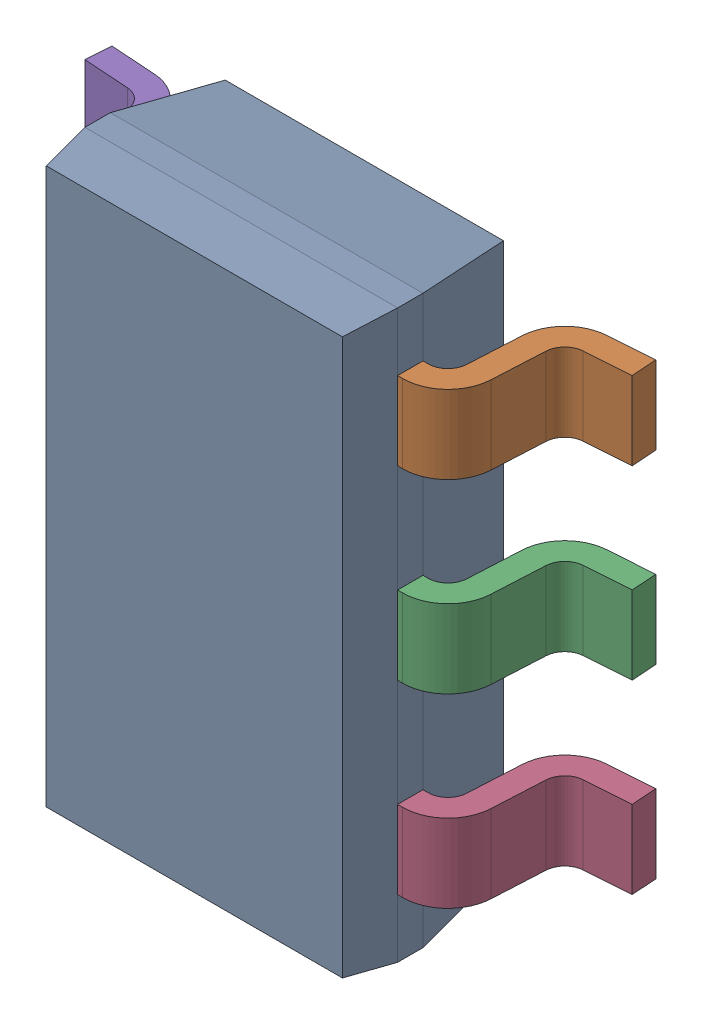
SolidWorks assembly DDC0006A, configuration ﾃﾞﾌｫﾙﾄ. Lengths in mm.
Overall size (2.8 2.9 0.97).
7 component instances, 2 part files, 0 mates.
Components (placement in the parent):
- BODY-SOT-1: BODY-SOT [ﾃﾞﾌｫﾙﾄ] at (0 0 0.73) x (0 1 0) z (1 0 0) size (2.9 0.87 1.6)
- LEAD-SOT-1: LEAD-SOT [ﾃﾞﾌｫﾙﾄ] at (0.9409 0.95 0.25) x (0 1 0) z (1 0 0) size (0.4 0.73 0.6)
- LEAD-SOT-2: LEAD-SOT [ﾃﾞﾌｫﾙﾄ] at (0.9409 0 0.25) x (0 1 0) z (1 0 0) size (0.4 0.73 0.6)
- LEAD-SOT-3: LEAD-SOT [ﾃﾞﾌｫﾙﾄ] at (0.9409 -0.95 0.25) x (0 1 0) z (1 0 0) size (0.4 0.73 0.6)
- LEAD-SOT-4: LEAD-SOT [ﾃﾞﾌｫﾙﾄ] at (-0.9409 0.95 0.25) x (0 -1 0) z (-1 0 0) size (0.4 0.73 0.6)
- LEAD-SOT-5: LEAD-SOT [ﾃﾞﾌｫﾙﾄ] at (-0.9409 0 0.25) x (0 -1 0) z (-1 0 0) size (0.4 0.73 0.6)
- LEAD-SOT-6: LEAD-SOT [ﾃﾞﾌｫﾙﾄ] at (-0.9409 -0.95 0.25) x (0 -1 0) z (-1 0 0) size (0.4 0.73 0.6)
